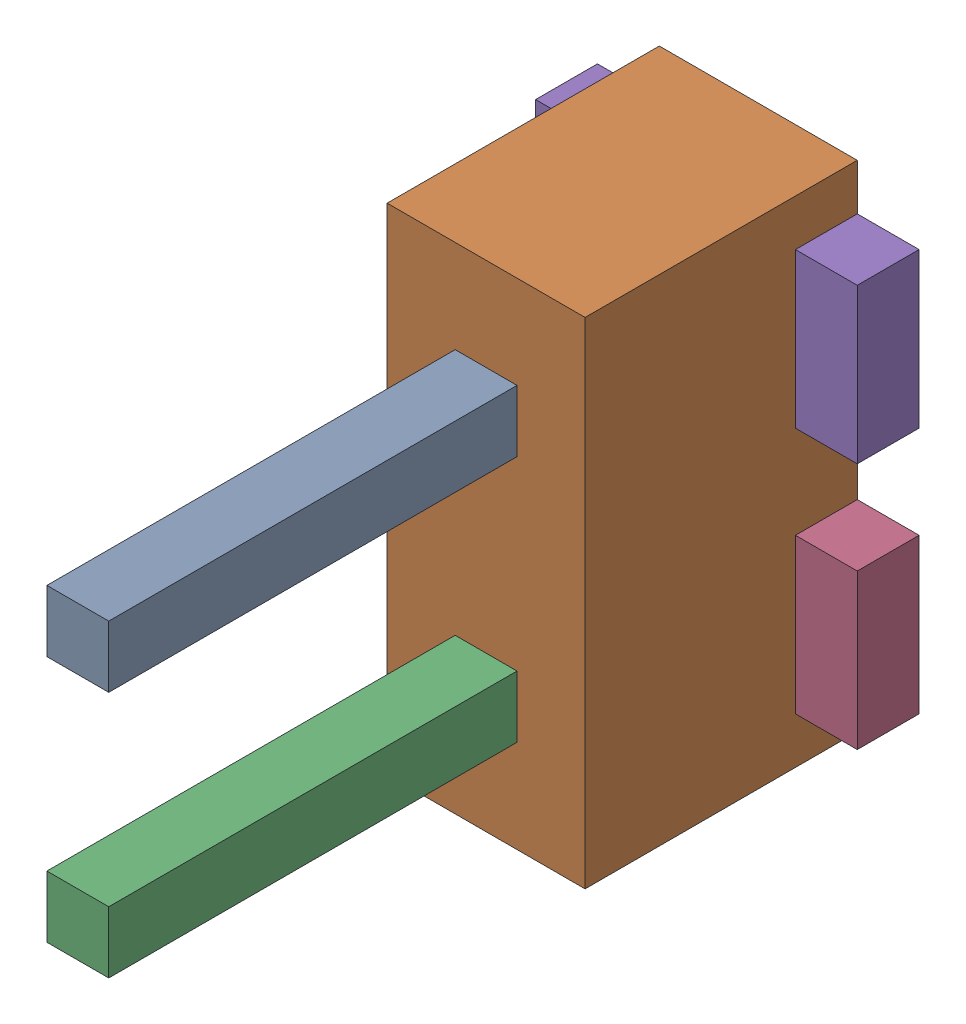
SolidWorks assembly J8, configuration ﾃﾞﾌｫﾙﾄ. Lengths in mm.
Overall size (2.6 4 5.5).
10 component instances, 3 part files, 0 mates.
Components (placement in the parent):
- 689260832-1: 689260832 [ﾃﾞﾌｫﾙﾄ] at (29.8 51.9001 2.2) size (0.5 0.5 3.3)
  - Extruded_26-1: Extruded_26 [ﾃﾞﾌｫﾙﾄ] at origin size (0.5 0.5 3.3)
- 689260968-1: 689260968 [ﾃﾞﾌｫﾙﾄ] at (29.8 50.9 0) size (1.6 4 2.2)
  - Extruded_27-1: Extruded_27 [ﾃﾞﾌｫﾙﾄ] at origin size (1.6 4 2.2)
- 689260832-2: 689260832 [ﾃﾞﾌｫﾙﾄ] at (29.8 49.9006 2.2) size (0.5 0.5 3.3)
  - Extruded_26-1: Extruded_26 [ﾃﾞﾌｫﾙﾄ] at origin size (0.5 0.5 3.3)
- 689261104-1: 689261104 [ﾃﾞﾌｫﾙﾄ] at (29.7999 49.9001 0) size (2.6 1.25 0.5)
  - Extruded_28-1: Extruded_28 [ﾃﾞﾌｫﾙﾄ] at origin size (2.6 1.25 0.5)
- 689261104-2: 689261104 [ﾃﾞﾌｫﾙﾄ] at (29.7999 51.9001 0) size (2.6 1.25 0.5)
  - Extruded_28-1: Extruded_28 [ﾃﾞﾌｫﾙﾄ] at origin size (2.6 1.25 0.5)
